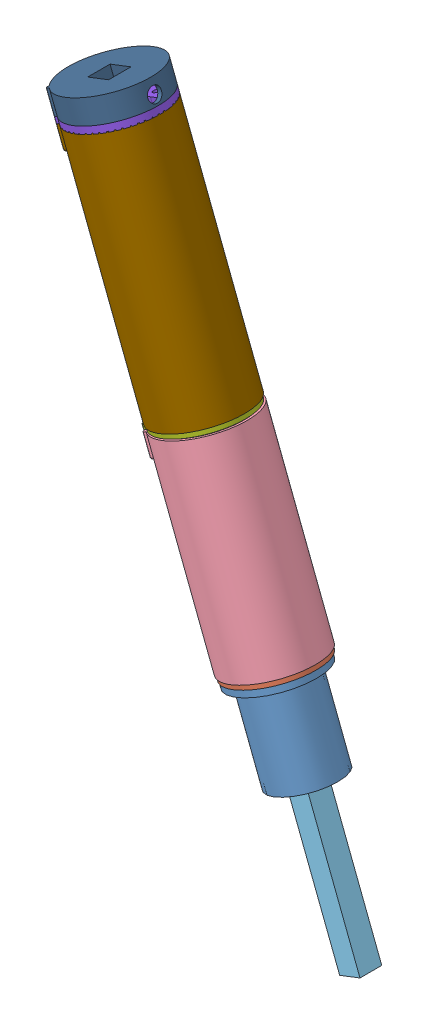
SolidWorks assembly twin_collective, configuration По умолчанию. Lengths in mm.
Overall size (137.41 305.79 46.19).
10 component instances, 10 part files, 24 mates.
Components (placement in the parent):
- twin_coll_decorative_cover_tcoll08-1: twin_coll_decorative_cover_tcoll08 [По умолчанию] at (-16.0057 107.3923 -0.675) x (0 0 -1) z (0.932972 0.359949 0) size (38 40 38)
- twin_coll_throttle2_frame_p1_tcoll09-1: twin_coll_throttle2_frame_p1_tcoll09 [По умолчанию] at (-46.9714 188.6959 -0.65) x (0.932972 0.359949 0) z (0 0 -1) size (39 77 39)
- twin_coll_throttle2_frame_p2_tcoll10-1: twin_coll_throttle2_frame_p2_tcoll10 [По умолчанию] at (-52.3707 202.6905 -0.65) x (-0.932972 -0.359949 0) z (0 0 -1) size (36 27 34)
- twin_coll_throttle2_grip_tcoll11-1: twin_coll_throttle2_grip_tcoll11 [По умолчанию] at (-30.7737 146.7121 -0.65) x (-0.92274 -0.356001 -0.147697) z (-0.359949 0.932972 0) size (40 40 86.4)
- alu_square_pipe_10x10x130-1: alu_square_pipe_10x10x130 [По умолчанию] at (8.6574 44.0222 -0.475) x (-0.932972 -0.359949 0) z (0 0 -1) size (9.9 130 9.9)
- alu_square_pipe_10x10x50-1: alu_square_pipe_10x10x50 [По умолчанию] at (-56.6901 213.8861 -0.475) x (0.932972 0.359949 0) z (0 0 1) size (9.9 50 9.9)
- twin_coll_throttle1_frame_p1_tcoll12-1: twin_coll_throttle1_frame_p1_tcoll12 [По умолчанию] at (-82.4431 281.1231 -0.3) x (0.932972 0.359949 0) z (0 0 -1) size (39 92 39)
- twin_coll_throttle1_frame_p2_tcoll13-2: twin_coll_throttle1_frame_p2_tcoll13 [По умолчанию] at (-87.8423 295.1177 -0.3) x (-0.932972 -0.359949 0) z (0 0 -1) size (40 39 40)
- twin_coll_throttle1_grip_tcoll14-1: twin_coll_throttle1_grip_tcoll14 [По умолчанию] at (-62.6459 229.8096 -0.3) x (-0.919515 -0.354757 -0.16923) z (-0.359949 0.932972 0) size (40 40 106.4)
- twin_coll_i2c_conn_housing_tcoll15-1: twin_coll_i2c_conn_housing_tcoll15 [По умолчанию] at (-101.8803 331.5036 -0.3) x (0 0 -1) z (0.932972 0.359949 0) size (40 10 40)
Mates (geometry in assembly coordinates):
- Coincident58: coincident anti-aligned: plane of twin_coll_throttle2_frame_p1_tcoll09-1 through (-30.7737 146.7121 -0.65) normal (-0.359949 0.932972 0); plane of twin_coll_throttle2_grip_tcoll11-1 through (-30.7737 146.7121 -0.65) normal (0.359949 -0.932972 0)
- Concentric15: concentric aligned: cylinder of twin_coll_throttle2_frame_p2_tcoll10-1 through (-62.0893 227.8807 -0.65) axis (0.359949 -0.932972 0) radius 18; cylinder of twin_coll_throttle2_grip_tcoll11-1 through (-61.8733 227.3209 -0.65) axis (0.359949 -0.932972 0) radius 18.5
- Coincident87: coincident anti-aligned: plane of twin_coll_throttle2_frame_p1_tcoll09-1 through (-49.2333 180.3203 -5.775) normal (0.932972 0.359949 0); plane of alu_square_pipe_10x10x130-1 through (-42.7542 163.5268 -5.425) normal (-0.932972 -0.359949 0)
- Coincident88: coincident anti-aligned: plane of twin_coll_throttle2_frame_p1_tcoll09-1 through (-49.2333 180.3203 4.475) normal (0 0 -1); plane of alu_square_pipe_10x10x130-1 through (-42.7542 163.5268 4.475) normal (0 0 1)
- Coincident90: coincident aligned: plane of twin_coll_throttle2_frame_p1_tcoll09-1 through (-37.9727 165.3716 -0.65) normal (-0.359949 0.932972 0); plane of alu_square_pipe_10x10x130-1 through (-38.136 165.3086 -0.475) normal (-0.359949 0.932972 0)
- Coincident91: coincident anti-aligned: plane of twin_coll_decorative_cover_tcoll08-1 through (-25.5989 146.565 4.475) normal (0 0 -1); plane of alu_square_pipe_10x10x130-1 through (-42.7542 163.5268 4.475) normal (0 0 1)
- Coincident92: coincident anti-aligned: plane of twin_coll_decorative_cover_tcoll08-1 through (-25.5989 146.565 -5.825) normal (-0.932972 -0.359949 0); plane of alu_square_pipe_10x10x130-1 through (-33.5178 167.0903 -5.425) normal (0.932972 0.359949 0)
- Concentric21: concentric anti-aligned: cylinder of twin_coll_throttle2_frame_p1_tcoll09-1 through (-30.7737 146.7121 -0.65) axis (-0.359949 0.932972 0) radius 18; cylinder of twin_coll_throttle2_grip_tcoll11-1 through (-61.8733 227.3209 -0.65) axis (0.359949 -0.932972 0) radius 18.5
- Parallel10: parallel anti-aligned: plane of twin_coll_throttle2_frame_p1_tcoll09-1 through (-43.3286 222.2566 -4.2771) normal (0.932972 0.359949 0); plane of twin_coll_throttle2_frame_p2_tcoll10-1 through (-43.1632 222.7492 4.8979) normal (-0.932972 -0.359949 0)
- Coincident119: coincident anti-aligned: plane of twin_coll_throttle2_frame_p1_tcoll09-1 through (-52.3707 202.6905 -0.65) normal (-0.359949 0.932972 0); plane of twin_coll_throttle2_frame_p2_tcoll10-1 through (-52.3707 202.6905 -0.65) normal (0.359949 -0.932972 0)
- Coincident120: coincident anti-aligned: circle of twin_coll_throttle2_frame_p2_tcoll10-1; cylinder of alu_square_pipe_10x10x50-1 through (-58.4898 218.551 4.475) axis (0 0 -1) radius 1.5
- Coincident125: coincident anti-aligned: plane of twin_coll_throttle2_frame_p2_tcoll10-1 through (-66.8708 226.036 4.475) normal (0 0 -1); plane of alu_square_pipe_10x10x50-1 through (-70.0693 262.3165 4.475) normal (0 0 1)
- Coincident126: coincident anti-aligned: plane of twin_coll_decorative_cover_tcoll08-1 through (-30.4037 144.7112 -0.675) normal (-0.359949 0.932972 0); plane of twin_coll_throttle2_frame_p1_tcoll09-1 through (-30.0538 144.8462 -0.65) normal (0.359949 -0.932972 0)
- Coincident135: coincident anti-aligned: plane of alu_square_pipe_10x10x50-1 through (-70.0693 262.3165 -5.425) normal (0 0 -1); plane of twin_coll_throttle1_frame_p1_tcoll12-1 through (-81.1055 263.4178 -5.425) normal (0 0 1)
- Coincident136: coincident anti-aligned: plane of alu_square_pipe_10x10x50-1 through (-79.3057 258.753 4.475) normal (-0.932972 -0.359949 0); plane of twin_coll_throttle1_frame_p1_tcoll12-1 through (-81.1055 263.4178 -5.425) normal (0.932972 0.359949 0)
- Coincident137: coincident anti-aligned: plane of twin_coll_throttle2_frame_p2_tcoll10-1 through (-62.0893 227.8807 -0.65) normal (-0.359949 0.932972 0); plane of twin_coll_throttle1_frame_p1_tcoll12-1 through (-61.926 227.9437 -0.3) normal (0.359949 -0.932972 0)
- Concentric29: concentric anti-aligned: cylinder of twin_coll_throttle1_frame_p1_tcoll12-1 through (-62.6459 229.8096 -0.3) axis (-0.359949 0.932972 0) radius 18; cylinder of twin_coll_throttle1_frame_p2_tcoll13-2 through (-100.8005 328.7047 -0.3) axis (0.359949 -0.932972 0) radius 18
- Parallel12: parallel anti-aligned: plane of twin_coll_throttle1_frame_p1_tcoll12-1 through (-80.6 319.3487 -3.9271) normal (0 0 -1); plane of twin_coll_throttle1_frame_p2_tcoll13-2 through (-80.4346 319.8413 -4.1021) normal (0 0 1)
- Coincident142: coincident anti-aligned: plane of twin_coll_throttle1_frame_p1_tcoll12-1 through (-87.8423 295.1177 -0.3) normal (-0.359949 0.932972 0); plane of twin_coll_throttle1_frame_p2_tcoll13-2 through (-87.8423 295.1177 -0.3) normal (0.359949 -0.932972 0)
- Concentric30: concentric aligned: cylinder of twin_coll_throttle1_frame_p2_tcoll13-2 through (-100.8005 328.7047 -0.3) axis (0.359949 -0.932972 0) radius 18; cylinder of twin_coll_throttle1_grip_tcoll14-1 through (-100.9445 329.0779 -0.3) axis (0.359949 -0.932972 0) radius 18.5
- Coincident143: coincident anti-aligned: plane of twin_coll_throttle1_frame_p1_tcoll12-1 through (-62.6459 229.8096 -0.3) normal (-0.359949 0.932972 0); plane of twin_coll_throttle1_grip_tcoll14-1 through (-62.6459 229.8096 -0.3) normal (0.359949 -0.932972 0)
- Concentric31: concentric aligned: cylinder of twin_coll_throttle1_frame_p2_tcoll13-2 through (-100.8005 328.7047 -0.3) axis (0.359949 -0.932972 0) radius 18; cylinder of twin_coll_i2c_conn_housing_tcoll15-1 through (-105.4798 340.8333 -0.3) axis (0.359949 -0.932972 0) radius 20
- Parallel13: parallel aligned: plane of twin_coll_throttle1_frame_p2_tcoll13-2 through (-96.019 330.5494 -5.425) normal (-0.932972 -0.359949 0); plane of twin_coll_i2c_conn_housing_tcoll15-1 through (-100.7217 342.6691 -5.4) normal (-0.932972 -0.359949 0)
- Coincident148: coincident anti-aligned: plane of twin_coll_throttle1_frame_p2_tcoll13-2 through (-101.8803 331.5036 -0.3) normal (-0.359949 0.932972 0); plane of twin_coll_i2c_conn_housing_tcoll15-1 through (-101.8803 331.5036 -0.3) normal (0.359949 -0.932972 0)
